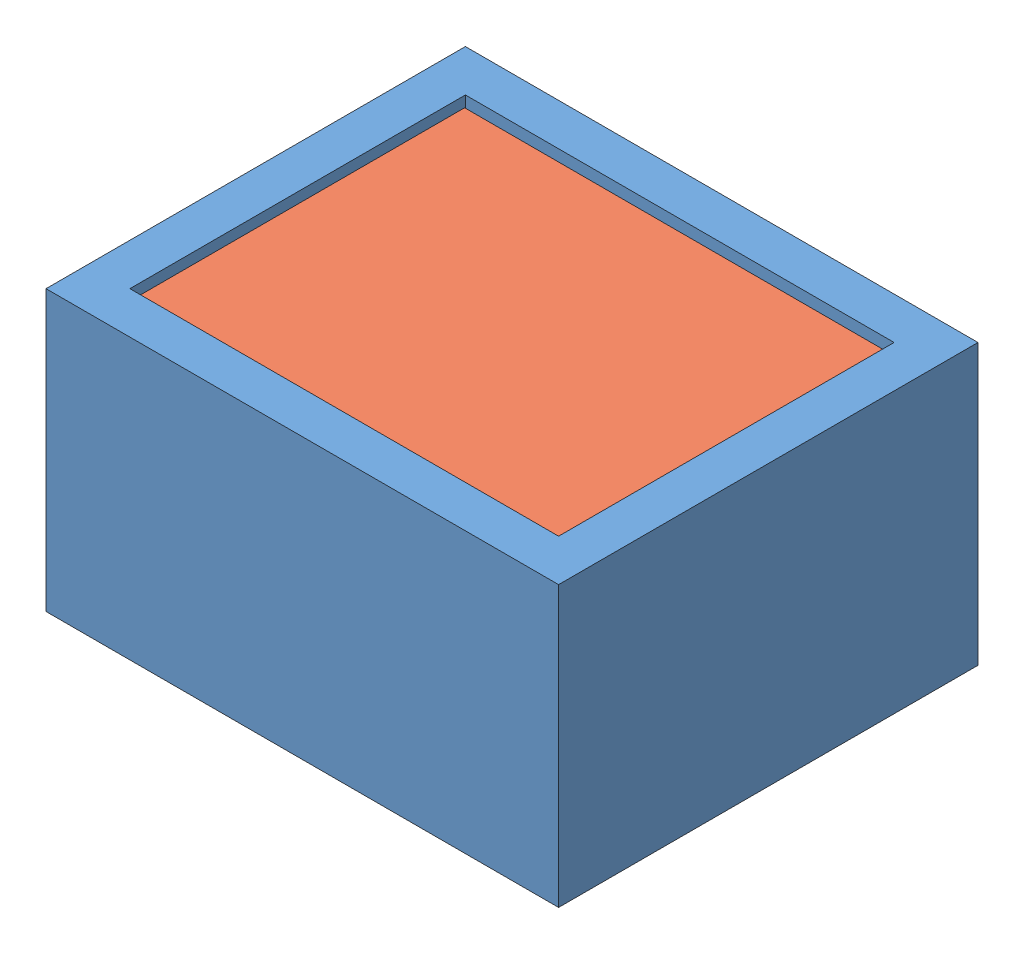
SolidWorks assembly Assem1, configuration Default. Lengths in mm.
Overall size (110 60 90).
2 component instances, 2 part files, 1 mates.
Components (placement in the parent):
- casing-1: casing [Default] at (-22.1291 24.4266 140.1828) size (110 60 90)
- PCB_model-1: PCB_model [Default] at (-12.2336 81.4266 130.251) size (90 1.6 70)
Mates (geometry in assembly coordinates):
- Coincident2: coincident: plane of casing-1 through (-22.1291 81.4266 140.1828) normal (0 1 0); plane of PCB_model-1 through (-12.2336 81.4266 130.251) normal (0 -1 0)
